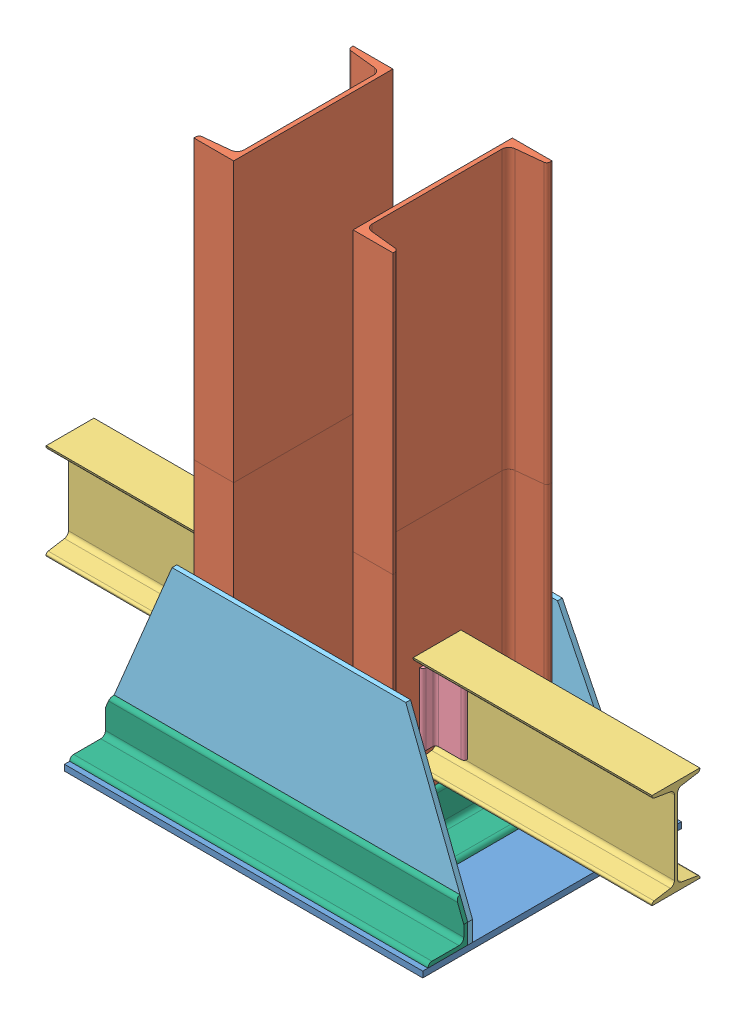
SolidWorks assembly Assem1, configuration Default. Lengths in mm.
Overall size (1522 1415 650).
17 component instances, 6 part files, 21 mates.
Components (placement in the parent):
- Base plate-1: Base plate [Default] at origin size (900 15 650)
- c channel_iso-1: c channel_iso [CH 400 x 59x700] at (150 365 -200) x (1 0 0) z (0 -1 0) size (100 400 700)
- c channel_iso-2: c channel_iso [CH 400 x 59x700] at (150 1065 -200) x (1 0 0) z (0 -1 0) size (100 400 700)
- sb beam_iso-2: sb beam_iso [SB 240 x 36x600] at (461 180 -60) x (0 0 1) z (-1 0 0) size (120 240 600)
- uneq angle_iso-2: uneq angle_iso [80x40x8x180] at (161 300 3.9) x (0 0 1) z (0 1 0) size (40 80 180)
- uneq angle_iso-4: uneq angle_iso [80x40x8x180] at (161 300 -3.9) x (0 0 -1) z (0 -1 0) size (40 80 180)
- c channel_iso-3: c channel_iso [CH 400 x 59x700] at (-150 365 -200) x (-1 0 0) z (0 1 0) size (100 400 700)
- c channel_iso-4: c channel_iso [CH 400 x 59x700] at (-150 1065 -200) x (-1 0 0) z (0 1 0) size (100 400 700)
- sb beam_iso-3: sb beam_iso [SB 240 x 36x600] at (-461 180 -60) x (0 0 1) z (-1 0 0) size (120 240 600)
- uneq angle_iso-5: uneq angle_iso [80x40x8x180] at (-161 300 3.9) x (0 0 1) z (0 -1 0) size (40 80 180)
- uneq angle_iso-6: uneq angle_iso [80x40x8x180] at (-161 300 -3.9) x (0 0 -1) z (0 1 0) size (40 80 180)
- Gusset plate-1: Gusset plate [Default] at (0 240 200) size (900 450 12)
- eq angle_iso-1: eq angle_iso [100x100x10x900] at (0 15 212) x (0 0 1) z (-1 0 0) size (100 100 900)
- Gusset plate-2: Gusset plate [Default] at (0 240 -212) size (900 450 12)
- eq angle_iso-2: eq angle_iso [100x100x10x900] at (0 15 -212) x (0 0 -1) z (1 0 0) size (100 100 900)
- eq angle_iso-3: eq angle_iso [100x100x10x300] at (161 15 0) size (100 100 300)
- eq angle_iso-4: eq angle_iso [100x100x10x300] at (-161 15 0) x (-1 0 0) z (0 0 -1) size (100 100 300)
Mates (geometry in assembly coordinates):
- Coincident1: coincident anti-aligned: plane of Base plate-1 through (-450 15 325) normal (0 1 0); plane of c channel_iso-1 through (178 15 -163.016) normal (0 -1 0)
- Distance2: distance = 200 mm aligned: plane of c channel_iso-1 through (150 365 -200) normal (0 0 1); plane of Base plate-1 through (0 0 0) normal (0 0 1)
- Distance4: distance = 150 mm anti-aligned: plane of c channel_iso-1 through (150 15 200) normal (-1 0 0)
- Coincident9: coincident anti-aligned: plane of c channel_iso-1 through (178 715 -163.016) normal (0 1 0); plane of c channel_iso-2 through (178 715 -163.016) normal (0 -1 0)
- Coincident10: coincident aligned: plane of c channel_iso-1 through (161 15 163.016) normal (1 0 0); plane of c channel_iso-2 through (161 715 163.016) normal (1 0 0)
- Coincident11: coincident aligned: plane of c channel_iso-1 through (250 15 200) normal (0 0 1); plane of c channel_iso-2 through (250 715 200) normal (0 0 1)
- Coincident13: coincident anti-aligned: plane of c channel_iso-1 through (161 15 163.016) normal (1 0 0); plane of sb beam_iso-2 through (161 206.8407 -15.9) normal (-1 0 0)
- Distance5: distance = 165 mm anti-aligned: plane of Base plate-1 through (-450 15 325) normal (0 1 0); plane of sb beam_iso-2 through (161 180 60) normal (0 -1 0)
- Distance6: distance = 140 mm anti-aligned: plane of c channel_iso-1 through (250 15 -200) normal (0 0 -1); plane of sb beam_iso-2 through (461 180 -60) normal (0 0 1)
- Coincident18: coincident anti-aligned: plane of sb beam_iso-2 through (161 393.1593 3.9) normal (0 0 1); plane of uneq angle_iso-2 through (241 390 3.9) normal (0 0 -1)
- Coincident19: coincident anti-aligned: plane of c channel_iso-1 through (161 15 163.016) normal (1 0 0); plane of uneq angle_iso-2 through (161 390 43.9) normal (-1 0 0)
- Distance7: distance = 30 mm aligned: plane of uneq angle_iso-2 through (176 390 18.9) normal (0 1 0); plane of sb beam_iso-2 through (161 420 -60) normal (0 1 0)
- Coincident21: coincident anti-aligned: plane of c channel_iso-4 through (-250 1415 200) normal (0 0 1); plane of Gusset plate-1 through (0 240 200) normal (0 0 -1)
- Coincident22: coincident anti-aligned: plane of Base plate-1 through (-450 15 325) normal (0 1 0); plane of Gusset plate-1 through (-450 15 212) normal (0 -1 0)
- Coincident23: coincident aligned: plane of Base plate-1 through (450 0 325) normal (1 0 0); plane of Gusset plate-1 through (450 15 212) normal (1 0 0)
- Coincident24: coincident anti-aligned: plane of Gusset plate-1 through (0 240 212) normal (0 0 1); plane of eq angle_iso-1 through (-450 115 212) normal (0 0 -1)
- Coincident25: coincident anti-aligned: plane of Base plate-1 through (-450 15 325) normal (0 1 0); plane of eq angle_iso-1 through (-450 15 312) normal (0 -1 0)
- Coincident26: coincident aligned: plane of Base plate-1 through (450 0 325) normal (1 0 0); plane of eq angle_iso-1 through (450 37 234) normal (1 0 0)
- Coincident29: coincident anti-aligned: plane of c channel_iso-1 through (161 15 163.016) normal (1 0 0); plane of eq angle_iso-3 through (161 115 150) normal (-1 0 0)
- Coincident30: coincident anti-aligned: plane of Base plate-1 through (-450 15 325) normal (0 1 0); plane of eq angle_iso-3 through (261 15 150) normal (0 -1 0)
- Distance8: distance = 50 mm aligned: plane of eq angle_iso-3 through (183 37 150) normal (0 0 1); plane of c channel_iso-1 through (250 15 200) normal (0 0 1)
